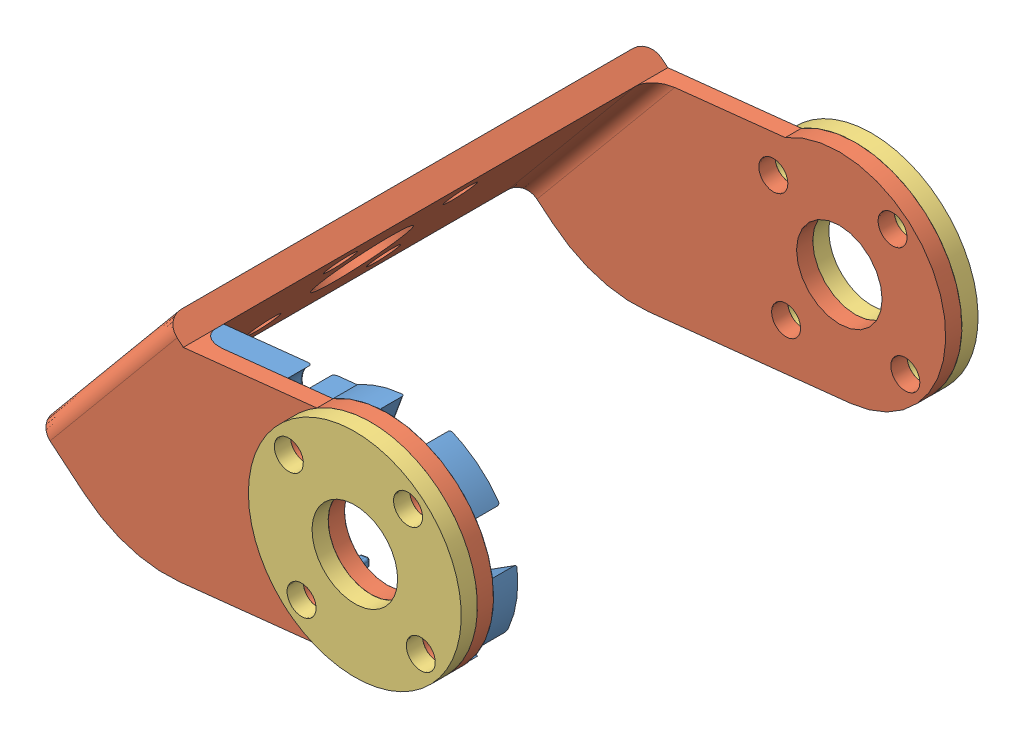
SolidWorks assembly box0_left_supplement, configuration Predeterminado. Lengths in mm.
Overall size (62.89 40.59 64).
5 component instances, 3 part files, 9 mates.
Components (placement in the parent):
- supplement_left_offset_f_horn-1: supplement_left_offset_f_horn [Predeterminado] at (12.685 58 45.7385) x (1 0 0) z (0 1 0) size (52.15 3.04 29.06)
- box0-1: box0 [Predeterminado] at (-0.1979 43.3658 47.7385) x (0.994321 0.106425 0) z (0 0 1) size (57.24 34.69 60)
  - offset_bracket-1: offset_bracket [Predeterminado] at (1.7542 14.53 -60) x (0.994321 -0.106425 0) z (-0.106425 -0.994321 0) size (54.46 60 29.06)
- suplement_external_bracket-1: suplement_external_bracket [Predeterminado] at (12.685 58 -12.2615) x (0.627837 0.778345 0) z (-0.778345 0.627837 0) size (26.36 2 26.36)
- suplement_external_bracket-2: suplement_external_bracket [Predeterminado] at (12.685 58 47.7385) x (0.778345 -0.627837 0) z (-0.627837 -0.778345 0) size (26.36 2 26.36)
Mates (geometry in assembly coordinates):
- Coincidente1: coincident anti-aligned: plane of supplement_left_offset_f_horn-1 through (12.685 58 45.7385) normal (0 0 1); plane of box0-1/offset_bracket-1 through (12.685 58 45.7385) normal (0 0 -1)
- Coincidente3: coincident anti-aligned: circle of supplement_left_offset_f_horn-1; cylinder of box0-1/offset_bracket-1 through (12.685 58 45.7385) axis (0 0 1) radius 5.3
- Coincidente4: coincident aligned: plane of supplement_left_offset_f_horn-1 through (14.0877 44.8949 42.7385) normal (0.106425 -0.994321 0); plane of box0-1/offset_bracket-1 through (14.0877 44.8949 45.7385) normal (0.106425 -0.994321 0)
- Concéntrica1: concentric: cylinder of box0-1/offset_bracket-1 through (12.685 58 -10.2615) axis (0 0 -1) radius 5.3; cylinder of suplement_external_bracket-1 through (12.685 58 -14.2615) axis (0 0 1) radius 5.3
- Concéntrica2: concentric: cylinder of box0-1/offset_bracket-1 through (4.5124 64.5923 -12.2615) axis (0 0 1) radius 1.8; cylinder of suplement_external_bracket-1 through (4.5124 64.5923 -12.2615) axis (0 0 -1) radius 1.8
- Coincidente5: coincident anti-aligned: plane of box0-1/offset_bracket-1 through (-12.685 58 -12.2615) normal (0 0 -1); plane of suplement_external_bracket-1 through (12.685 58 -12.2615) normal (0 0 1)
- Concéntrica3: concentric: cylinder of box0-1/offset_bracket-1 through (12.685 58 45.7385) axis (0 0 1) radius 5.3; cylinder of suplement_external_bracket-2 through (12.685 58 49.7385) axis (0 0 -1) radius 5.3
- Concéntrica4: concentric: cylinder of box0-1/offset_bracket-1 through (4.5124 64.5923 45.7385) axis (0 0 1) radius 1.8; cylinder of suplement_external_bracket-2 through (4.5124 64.5923 47.7385) axis (0 0 1) radius 1.8
- Coincidente6: coincident anti-aligned: plane of box0-1/offset_bracket-1 through (-12.0916 68.8599 47.7385) normal (0 0 1); plane of suplement_external_bracket-2 through (12.685 58 47.7385) normal (0 0 -1)
